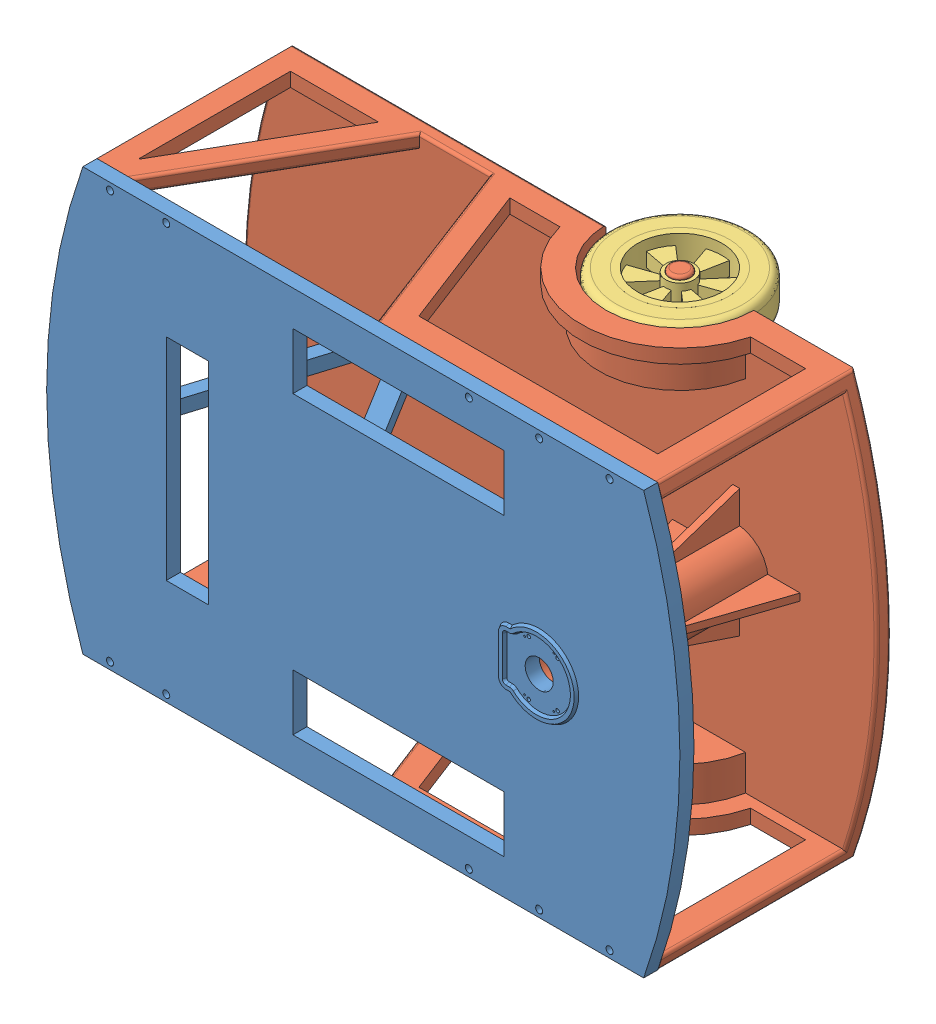
SolidWorks assembly mobile_platform, configuration 默认. Lengths in mm.
Overall size (900 600 437.62).
6 component instances, 5 part files, 11 mates.
Components (placement in the parent):
- frame_up-1: frame_up [默认] at origin size (900 600 284)
- frame-1: frame [默认] at (-100 0 -300) x (0 -1 0) z (-1 0 0) size (600 300 900)
- forewheel-1: forewheel [默认] at (-100 -275 -300) x (0.967058 0 -0.254554) z (0.254554 0 0.967058) size (200 50 200)
- forewheel-2: forewheel [默认] at (-100 275 -300) x (0.899669 0 0.436572) z (-0.436572 0 0.899669) size (200 50 200)
- rearwheel_1-1: rearwheel_1 [默认] at (-500 0 -310) x (1 0 0) z (0 1 0) size (85 75 40)
- rearwheel_2-1: rearwheel_2 [默认] at (-550 0 -370) x (0.996859 0 0.0792) z (-0.0792 0 0.996859) size (60 30 60)
Mates (geometry in assembly coordinates):
- 重合1: coincident anti-aligned: plane of frame_up-1 through (0 0 -20) normal (0 0 -1); plane of frame-1 through (-600 -310 -20) normal (0 0 1)
- 重合2: coincident aligned: plane of frame_up-1 through (-700 -300 -20) normal (0 -1 0); plane of frame-1 through (-100 -300 -300) normal (0 -1 0)
- 同心1: concentric anti-aligned: cylinder of frame_up-1 through (0 0 -20) axis (0 0 1) radius 20; cylinder of frame-1 through (0 0 -20) axis (0 0 -1) radius 45
- 同心2: concentric aligned: cylinder of frame-1 through (-100 300 -300) axis (0 -1 0) radius 10; cylinder of forewheel-1 through (-100 -250 -300) axis (0 -1 0) radius 10
- 重合3: coincident anti-aligned: plane of frame-1 through (-100 -255 -300) normal (0 -1 0); plane of forewheel-1 through (-100 -255 -300) normal (0 1 0)
- 同心3: concentric aligned: cylinder of frame-1 through (-100 300 -300) axis (0 -1 0) radius 10; cylinder of forewheel-2 through (-100 300 -300) axis (0 -1 0) radius 10
- 重合4: coincident anti-aligned: plane of frame-1 through (-100 255 -300) normal (0 1 0); plane of forewheel-2 through (-100 255 -300) normal (0 -1 0)
- 同心4: concentric aligned: cylinder of frame-1 through (-500 0 -320) axis (0 0 1) radius 5; cylinder of rearwheel_1-1 through (-500 0 -350) axis (0 0 1) radius 5
- 重合5: coincident anti-aligned: plane of frame-1 through (-500 0 -310) normal (0 0 -1); plane of rearwheel_1-1 through (-500 0 -310) normal (0 0 1)
- 同心5: concentric anti-aligned: cylinder of rearwheel_1-1 through (-550 35 -370) axis (0 -1 0) radius 5; cylinder of rearwheel_2-1 through (-550 -15 -370) axis (0 1 0) radius 5
- 重合6: coincident aligned: plane of rearwheel_1-1 through (-550 15 -370) normal (0 1 0); plane of rearwheel_2-1 through (-550 15 -370) normal (0 1 0)
